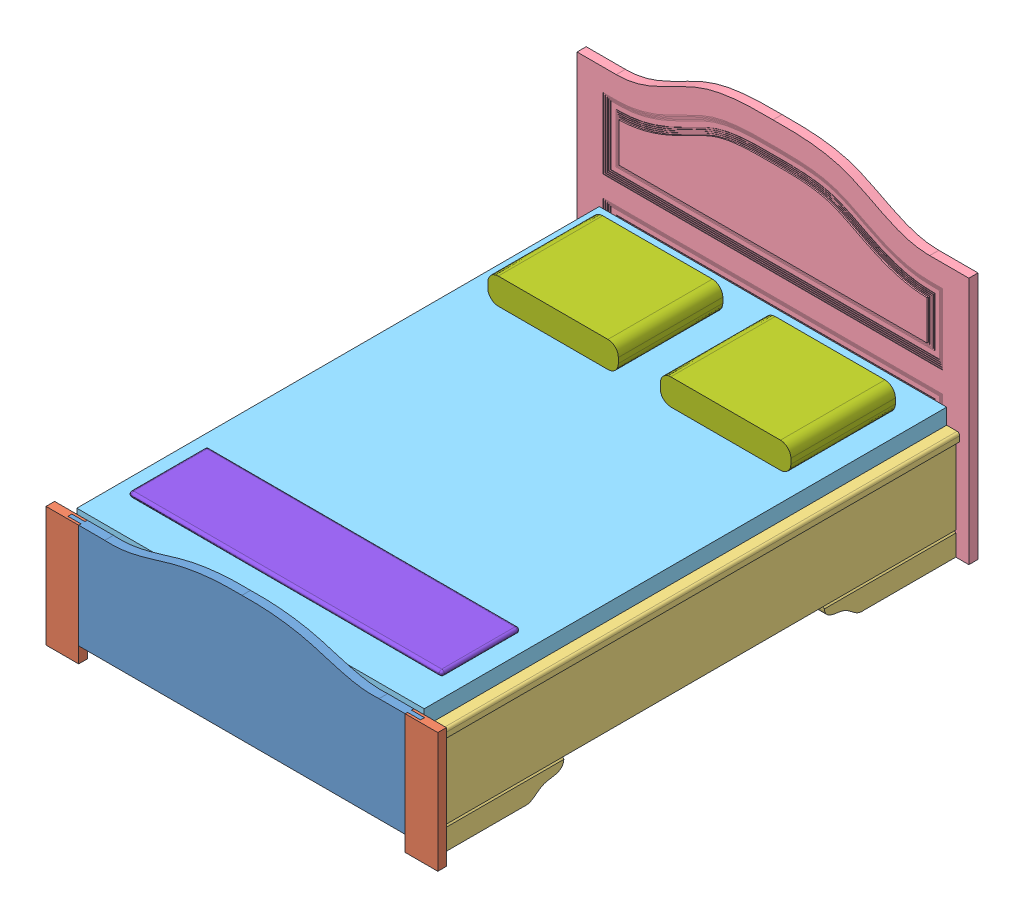
SolidWorks assembly Bed-Assembly., configuration Default. Lengths in mm.
Overall size (1500 1102.82 2068).
11 component instances, 8 part files, 25 mates.
Components (placement in the parent):
- B-Part 01-1: B-Part 01 [Default] at (772.6563 936.4063 916.1575) size (1350 482.1 33)
- B-Part 02-1: B-Part 02 [Default] at (147.6563 856.4063 916.1575) size (125 460 33)
- B-Part 03-1: B-Part 03 [Default] at (1437.6563 816.4063 -1083.8425) x (0 0 -1) z (1 0 0) size (2000 421.85 80)
- B-Part 04-1: B-Part 04 [Default] at (772.6563 1346.4063 -1118.8425) size (1500 1100.97 36)
- B-Part 02-2: B-Part 02 [Default] at (1397.6563 856.4063 949.1575) x (-1 0 0) z (0 0 -1) size (125 460 33)
- B-Part 03-2: B-Part 03 [Default] at (107.6563 816.4063 916.1575) x (0 0 1) z (-1 0 0) size (2000 421.85 80)
- B-Part 05-1: B-Part 05 [Default] at (107.6563 876.4063 916.1575) x (1 0 0) z (0 -1 0) size (1330 2000 150)
- B-Part 06-1: B-Part 06 [Default] at (107.6563 726.4063 916.1575) x (1 0 0) z (0 -1 0) size (1330 1900 60)
- B-Part 07-1: B-Part 07 [Default] at (704.6802 976.4063 -960.0587) x (0 0 1) z (-1 0 0) size (400 100 500)
- B-Part 07-2: B-Part 07 [Default] at (1369.0904 976.4063 -956.2175) x (0 0 1) z (-1 0 0) size (400 100 500)
- B-Part 08-2: B-Part 08 [Default] at (169.7035 886.4063 780.2976) x (1 0 0.000762) z (0 -1 0) size (1200 300 20)
Mates (geometry in assembly coordinates):
- Coincident1: coincident anti-aligned: plane of Part 01-1 through (147.6563 456.4063 925.1575) normal (0 0 -1); plane of Part 02-1 through (147.6563 456.4063 925.1575) normal (0 0 1)
- Coincident2: coincident anti-aligned: plane of Part 01-1 through (97.6563 456.4063 925.1575) normal (-1 0 0); plane of Part 02-1 through (97.6563 456.4063 925.1575) normal (1 0 0)
- Coincident3: coincident aligned: plane of Part 01-1 through (247.6563 856.4063 949.1575) normal (0 1 0); plane of Part 02-1 through (147.6563 856.4063 949.1575) normal (0 1 0)
- Coincident4: coincident anti-aligned: plane of Part 01-1 through (1397.6563 456.4063 925.1575) normal (0 0 -1); plane of Part 02-2 through (1397.6563 456.4063 925.1575) normal (0 0 1)
- Coincident5: coincident aligned: plane of Part 01-1 through (1297.6563 856.4063 949.1575) normal (0 1 0); plane of Part 02-2 through (1397.6563 856.4063 916.1575) normal (0 1 0)
- Coincident6: coincident anti-aligned: plane of Part 01-1 through (1447.6563 456.4063 925.1575) normal (1 0 0); plane of Part 02-2 through (1447.6563 456.4063 940.1575) normal (-1 0 0)
- Coincident7: coincident anti-aligned: plane of Part 03-1 through (1487.6563 816.4063 -1083.8425) normal (0 0 -1); plane of Part 04-1 through (465.671 1452.0302 -1083.8425) normal (0 0 1)
- Coincident8: coincident aligned: plane of Part 03-1 through (1437.6563 396.4063 -729.876) normal (0 -1 0); plane of Part 04-1 through (772.6563 396.4063 -1083.8425) normal (0 -1 0)
- Distance1: distance = 50 mm: line of Part 04-1 through (1522.6563 1346.4063 -1083.8425) axis (0 -1 0); line of Part 03-1 through (1472.6563 786.4063 -1083.8425) axis (0 -1 0)
- Coincident10: coincident anti-aligned: plane of Part 04-1 through (465.671 1452.0302 -1083.8425) normal (0 0 1); plane of Part 03-2 through (57.6563 816.4063 -1083.8425) normal (0 0 -1)
- Coincident11: coincident aligned: plane of Part 04-1 through (772.6563 396.4063 -1083.8425) normal (0 -1 0); plane of Part 03-2 through (107.6563 396.4063 -1083.8425) normal (0 -1 0)
- Distance2: distance = 50 mm: line of Part 04-1 through (22.6563 1346.4063 -1083.8425) axis (0 -1 0); line of Part 03-2 through (72.6563 486.4063 -1083.8425) axis (0 1 0)
- Coincident13: coincident anti-aligned: plane of Part 02-1 through (147.6563 856.4063 916.1575) normal (0 0 -1); plane of Part 03-2 through (57.6563 816.4063 916.1575) normal (0 0 1)
- Coincident14: coincident anti-aligned: plane of Part 03-1 through (1487.6563 816.4063 916.1575) normal (0 0 1); plane of Part 02-2 through (1397.6563 856.4063 916.1575) normal (0 0 -1)
- Distance3: distance = 50 mm: line of Part 02-2 through (1522.6563 856.4063 916.1575) axis (0 -1 0); line of Part 03-1 through (1472.6563 486.4063 916.1575) axis (0 1 0)
- Coincident18: coincident aligned: plane of Part 02-1 through (147.6563 396.4063 949.1575) normal (0 -1 0); plane of Part 03-2 through (107.6563 396.4063 562.1911) normal (0 -1 0)
- Coincident19: coincident anti-aligned: plane of Part 03-1 through (1437.6563 816.4063 -1083.8425) normal (-1 0 0); plane of Part 06-1 through (1437.6563 696.4063 916.1575) normal (1 0 0)
- Distance5: distance = 50 mm anti-aligned: plane of Part 04-1 through (772.6563 1346.4063 -1083.8425) normal (0 0 1); plane of Part 06-1 through (107.6563 696.4063 -1033.8425) normal (0 0 -1)
- Coincident21: coincident anti-aligned: plane of Part 03-1 through (1407.6563 666.4063 -1083.8425) normal (0 1 0); plane of Part 06-1 through (107.6563 666.4063 916.1575) normal (0 -1 0)
- Coincident22: coincident anti-aligned: plane of Part 05-1 through (107.6563 726.4063 916.1575) normal (0 -1 0); plane of Part 06-1 through (107.6563 726.4063 916.1575) normal (0 1 0)
- Coincident23: coincident anti-aligned: plane of Part 04-1 through (772.6563 1346.4063 -1083.8425) normal (0 0 1); plane of Part 05-1 through (107.6563 726.4063 -1083.8425) normal (0 0 -1)
- Coincident24: coincident anti-aligned: plane of Part 03-1 through (1437.6563 816.4063 -1083.8425) normal (-1 0 0); plane of Part 05-1 through (1437.6563 726.4063 916.1575) normal (1 0 0)
- Coincident25: coincident anti-aligned: plane of Part 05-1 through (107.6563 876.4063 916.1575) normal (0 1 0); plane of Part 07-2 through (869.0904 876.4063 -956.2175) normal (0 -1 0)
- Coincident26: coincident anti-aligned: plane of Part 05-1 through (107.6563 876.4063 916.1575) normal (0 1 0); plane of Part 07-1 through (204.6802 876.4063 -960.0587) normal (0 -1 0)
- Coincident27: coincident anti-aligned: plane of Part 05-1 through (107.6563 876.4063 916.1575) normal (0 1 0); plane of Part 08-2 through (169.7035 876.4063 780.2976) normal (0 -1 0)
